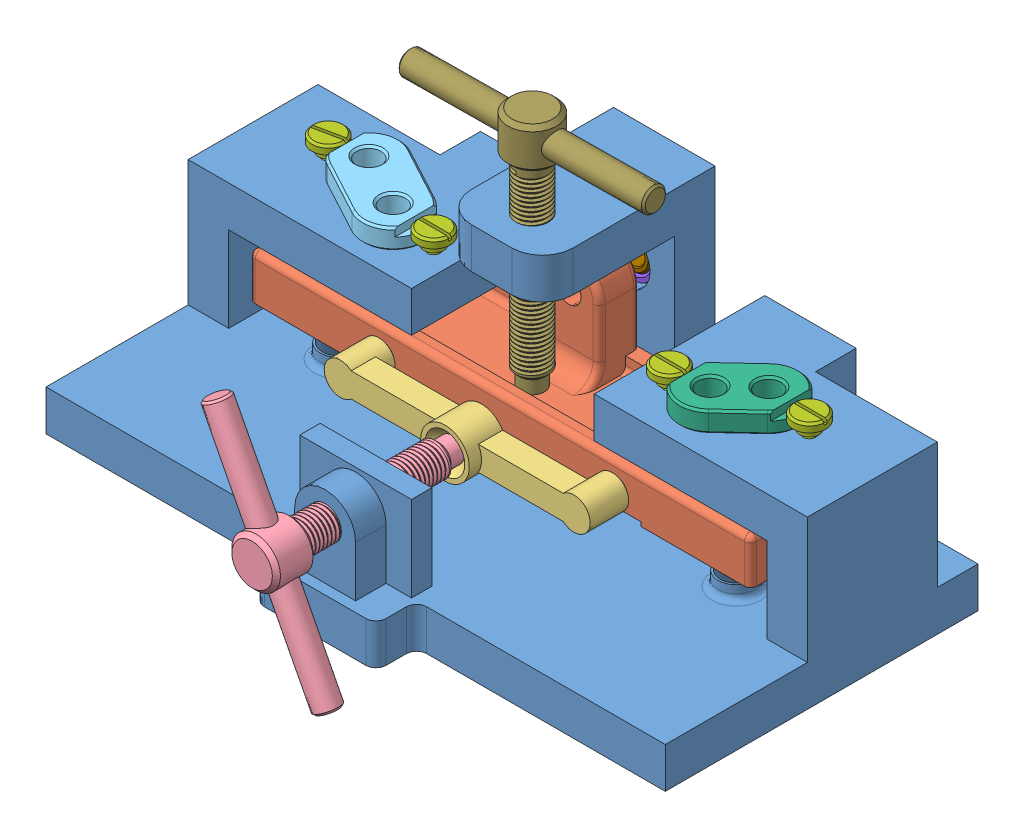
SolidWorks assembly 钻床夹具装配体1, configuration 默认. Lengths in mm.
Overall size (305 182.8 215).
22 component instances, 14 part files, 47 mates.
Components (placement in the parent):
- 钻床夹具（改）-1: 钻床夹具（改） [默认] at (208.9137 157.1071 193.3387) x (1 0 0) z (0 1 0) size (305 174 125.59)
- 前横架-1: 前横架 [默认] at (331.4137 192.1071 164.3387) x (-1 0 0) z (0 1 0) size (247 54 64)
- 压紧杆-1: 压紧杆 [默认] at (151.4137 203.1071 228.3387) size (131 24 28)
- 固定手柄压紧螺钉-1: 固定手柄压紧螺钉 [默认] at (208.9137 203.1071 341.3387) x (-0.887983 -0.459876 0) z (-0.459876 0.887983 0) size (24 100 120)
- 特殊钻套1-1: 特殊钻套1 [默认] at (135.4137 223.1071 198.3387) x (1 0 0) z (0 1 0) size (56 44 26)
- 特殊钻套2-1: 特殊钻套2 [默认] at (291.4137 223.1071 198.3387) x (1 0 0) z (0 1 0) size (45 44 26)
- 钻套螺钉M6×4-1: 钻套螺钉M6×4 [默认] at (89.4137 231.1071 184.3387) x (0.979036 0 -0.203686) z (0.203686 0 0.979036) size (16 18 16)
- 钻套螺钉M6×4-2: 钻套螺钉M6×4 [默认] at (155.4137 231.1071 198.3387) size (16 18 16)
- 钻套螺钉M6×4-3: 钻套螺钉M6×4 [默认] at (271.4137 231.1071 198.3387) size (16 18 16)
- 钻套螺钉M6×4-4: 钻套螺钉M6×4 [默认] at (326.4137 231.1071 184.3387) size (16 18 16)
- 衬套-1: 衬套 [默认] at (206.9137 241.1071 152.3387) x (1 0 0) z (0 1 0) size (30 16 30)
- 可换钻套-1: 可换钻套 [默认] at (206.9137 241.1071 152.3387) x (-0.095615 -0.995418 0) z (0.995418 -0.095615 0) size (30 26 30)
- 钻套螺钉M6×4-5: 钻套螺钉M6×4 [默认] at (206.9137 221.1071 144.3387) x (0.928637 -0.37099 0) z (0.37099 0.928637 0) size (16 18 16)
- A型支承钉-1: A型支承钉 [默认] at (131.4137 192.1071 176.3387) size (16 20 16)
- A型支承钉-2: A型支承钉 [默认] at (116.4137 192.1071 206.3387) size (16 20 16)
- A型支承钉-3: A型支承钉 [默认] at (311.4137 192.1071 205.3387) size (16 20 16)
- 辅助支撑螺柱-1: 辅助支撑螺柱 [默认] at (206.9137 173.7633 201.3387) x (0.999421 0 0.034011) z (-0.034011 0 0.999421) size (10 40 10)
- Z向夹紧手柄-2: Z向夹紧手柄 [默认] at (206.9137 327.1071 201.3387) x (-0.009902 0 -0.999951) z (0.999951 0 -0.009902) size (24 120 120)
- hex nuts, style 1-grades ab gb-1: hex nuts, style 1-grades ab gb [GB_FASTENER_NUT_SNAB1 M10-S] at (206.9137 177.1071 201.3387) x (1 0 0) z (0 -1 0) size (18.48 16 8.4)
- B型支承钉-1: B型支承钉 [默认] at (84.4137 203.1071 193.3387) x (0 -1 0) z (0 0 1) size (16 20 16)
- B型支承钉-2: B型支承钉 [默认] at (141.4137 203.1071 164.3387) x (1 0 0) z (0 -1 0) size (16 20 16)
- B型支承钉-3: B型支承钉 [默认] at (276.4137 203.1071 164.3387) x (1 0 0) z (0 -1 0) size (16 20 16)
Mates (geometry in assembly coordinates):
- 同心1: concentric: cylinder of assembly; cylinder of assembly; cylinder of 钻床夹具（改）-1 through (131.4137 157.1071 176.3387) axis (0 1 0) radius 5; cylinder of A型支承钉-1 through (131.4137 172.1071 176.3387) axis (0 -1 0) radius 5
- 重合1: coincident: plane of assembly; plane of assembly; plane of 钻床夹具（改）-1 through (131.4137 184.1071 176.3387) normal (0 1 0); plane of A型支承钉-1 through (139.4137 184.1071 176.3387) normal (0 -1 0)
- 同心2: concentric: cylinder of assembly; cylinder of assembly; cylinder of 钻床夹具（改）-1 through (116.4137 157.1071 206.3387) axis (0 1 0) radius 5; cylinder of A型支承钉-2 through (116.4137 172.1071 206.3387) axis (0 -1 0) radius 5
- 重合2: coincident: plane of assembly; plane of assembly; plane of 钻床夹具（改）-1 through (116.4137 184.1071 206.3387) normal (0 1 0); plane of A型支承钉-2 through (124.4137 184.1071 206.3387) normal (0 -1 0)
- 同心3: concentric: cylinder of assembly; cylinder of assembly; cylinder of 钻床夹具（改）-1 through (311.4137 157.1071 205.3387) axis (0 1 0) radius 5; cylinder of A型支承钉-3 through (311.4137 172.1071 205.3387) axis (0 -1 0) radius 5
- 重合3: coincident: plane of assembly; plane of assembly; plane of 钻床夹具（改）-1 through (311.4137 184.1071 205.3387) normal (0 1 0); plane of A型支承钉-3 through (319.4137 184.1071 205.3387) normal (0 -1 0)
- 同心4: concentric: cylinder of assembly; cylinder of assembly; cylinder of 钻床夹具（改）-1 through (291.4137 157.1061 198.3387) axis (0 1 0) radius 9; cylinder of 特殊钻套2-1 through (291.4137 239.1071 198.3387) axis (0 -1 0) radius 9
- 同心5: concentric: cylinder of assembly; cylinder of assembly; cylinder of 钻床夹具（改）-1 through (306.4137 157.1061 184.3387) axis (0 1 0) radius 9; cylinder of 特殊钻套2-1 through (306.4137 239.1071 184.3387) axis (0 -1 0) radius 9
- 重合5: coincident: plane of assembly; plane of assembly; plane of 钻床夹具（改）-1 through (208.9137 239.1071 193.3387) normal (0 1 0); plane of 特殊钻套2-1 through (291.4137 239.1071 198.3387) normal (0 -1 0)
- 同心6: concentric: cylinder of assembly; cylinder of assembly; cylinder of 钻床夹具（改）-1 through (135.4137 157.1061 198.3387) axis (0 1 0) radius 9; cylinder of 特殊钻套1-1 through (135.4137 239.1071 198.3387) axis (0 -1 0) radius 9
- 同心7: concentric: cylinder of assembly; cylinder of assembly; cylinder of 钻床夹具（改）-1 through (109.4137 157.1061 184.3387) axis (0 1 0) radius 9; cylinder of 特殊钻套1-1 through (109.4137 239.1071 184.3387) axis (0 -1 0) radius 9
- 重合6: coincident: plane of assembly; plane of assembly; plane of 钻床夹具（改）-1 through (208.9137 239.1071 193.3387) normal (0 1 0); plane of 特殊钻套1-1 through (135.4137 239.1071 198.3387) normal (0 -1 0)
- 同心8: concentric: cylinder of assembly; cylinder of assembly; cylinder of 钻床夹具（改）-1 through (271.4137 229.1071 198.3387) axis (0 1 0) radius 3; cylinder of 钻套螺钉M6×4-3 through (271.4137 249.1071 198.3387) axis (0 1 0) radius 3
- 重合7: coincident: plane of assembly; plane of assembly; plane of 特殊钻套2-1 through (291.4137 245.1071 198.3387) normal (0 1 0); plane of 钻套螺钉M6×4-3 through (276.1637 245.1071 198.3387) normal (0 -1 0)
- 同心9: concentric: cylinder of assembly; cylinder of assembly; cylinder of 钻床夹具（改）-1 through (326.4137 229.1071 184.3387) axis (0 1 0) radius 3; cylinder of 钻套螺钉M6×4-4 through (326.4137 249.1071 184.3387) axis (0 1 0) radius 3
- 重合8: coincident: plane of assembly; plane of assembly; plane of 特殊钻套2-1 through (306.4137 245.1071 184.3387) normal (0 1 0); plane of 钻套螺钉M6×4-4 through (331.1637 245.1071 184.3387) normal (0 -1 0)
- 同心10: concentric: cylinder of assembly; cylinder of assembly; cylinder of 钻床夹具（改）-1 through (155.4137 229.1071 198.3387) axis (0 1 0) radius 3; cylinder of 钻套螺钉M6×4-2 through (155.4137 249.1071 198.3387) axis (0 1 0) radius 3
- 重合9: coincident: plane of assembly; plane of assembly; plane of 特殊钻套1-1 through (135.4137 245.1071 198.3387) normal (0 1 0); plane of 钻套螺钉M6×4-2 through (160.1637 245.1071 198.3387) normal (0 -1 0)
- 同心11: concentric: cylinder of assembly; cylinder of assembly; cylinder of 钻床夹具（改）-1 through (89.4137 229.1071 184.3387) axis (0 1 0) radius 3; cylinder of 钻套螺钉M6×4-1 through (89.4137 249.1071 184.3387) axis (0 1 0) radius 3
- 重合10: coincident: plane of assembly; plane of assembly; plane of 特殊钻套1-1 through (109.4137 245.1071 184.3387) normal (0 1 0); plane of 钻套螺钉M6×4-1 through (94.0641 245.1071 183.3712) normal (0 -1 0)
- 同心12: concentric: cylinder of assembly; cylinder of assembly; cylinder of 钻床夹具（改）-1 through (361.4147 203.1071 193.3387) axis (-1 0 0) radius 5; cylinder of B型支承钉-1 through (64.4137 203.1071 193.3387) axis (-1 0 0) radius 5
- 重合11: coincident: plane of assembly; plane of assembly; plane of 钻床夹具（改）-1 through (76.4137 219.1071 193.3387) normal (1 0 0); plane of B型支承钉-1 through (76.4137 195.1071 193.3387) normal (-1 0 0)
- 同心13: concentric: cylinder of assembly; cylinder of assembly; cylinder of 钻床夹具（改）-1 through (141.4137 203.1071 310.3397) axis (0 0 -1) radius 5; cylinder of B型支承钉-2 through (141.4137 203.1071 144.3387) axis (0 0 -1) radius 5
- 重合12: coincident: plane of assembly; plane of assembly; plane of 钻床夹具（改）-1 through (166.4137 219.1071 156.3387) normal (0 0 1); plane of B型支承钉-2 through (149.4137 203.1071 156.3387) normal (0 0 -1)
- 同心14: concentric: cylinder of assembly; cylinder of assembly; cylinder of 钻床夹具（改）-1 through (276.4137 203.1071 310.3397) axis (0 0 -1) radius 5; cylinder of B型支承钉-3 through (276.4137 203.1071 144.3387) axis (0 0 -1) radius 5
- 重合13: coincident: plane of assembly; plane of assembly; plane of 钻床夹具（改）-1 through (208.9137 219.1071 156.3387) normal (0 0 1); plane of B型支承钉-3 through (284.4137 203.1071 156.3387) normal (0 0 -1)
- 同心15: concentric: cylinder of assembly; cylinder of assembly; cylinder of 钻床夹具（改）-1 through (206.9137 241.1071 156.3387) axis (0 0 -1) radius 13; cylinder of 衬套-1 through (206.9137 241.1071 136.3387) axis (0 0 -1) radius 13
- 重合14: coincident: plane of assembly; plane of assembly; plane of 钻床夹具（改）-1 through (206.9137 241.1071 139.3387) normal (0 0 -1); plane of 衬套-1 through (218.9137 241.1071 139.3387) normal (0 0 1)
- 同心16: concentric: cylinder of assembly; cylinder of assembly; cylinder of 衬套-1 through (206.9137 241.1071 152.3387) axis (0 0 -1) radius 9; cylinder of 可换钻套-1 through (206.9137 241.1071 126.3387) axis (0 0 -1) radius 9
- 重合15: coincident: plane of assembly; plane of assembly; plane of 衬套-1 through (221.9137 241.1071 136.3387) normal (0 0 -1); plane of 可换钻套-1 through (206.9137 241.1071 136.3387) normal (0 0 1)
- 同心17: concentric: cylinder of assembly; cylinder of assembly; cylinder of 钻床夹具（改）-1 through (206.9137 221.1071 151.3387) axis (0 0 -1) radius 3; cylinder of 钻套螺钉M6×4-5 through (206.9137 221.1071 126.3387) axis (0 0 -1) radius 3
- 重合16: coincident: plane of assembly; plane of assembly; plane of 可换钻套-1 through (206.9137 241.1071 130.3387) normal (0 0 -1); plane of 钻套螺钉M6×4-5 through (211.3247 219.3449 130.3387) normal (0 0 1)
- 重合17: coincident: plane of assembly; plane of assembly; plane of 前横架-1 through (331.4137 192.1071 164.3387) normal (0 -1 0); plane of A型支承钉-2 through (116.4137 192.1071 206.3387) normal (0 1 0)
- 相切1: tangent: plane of assembly; sphere of assembly; plane of 前横架-1 through (84.4137 214.1071 164.3387) normal (-1 0 0); sphere of B型支承钉-1
- 相切2: tangent: plane of assembly; sphere of assembly; plane of 前横架-1 through (331.4137 214.1071 164.3387) normal (0 0 -1); sphere of B型支承钉-3
- 同心18: concentric: circle of assembly; circle of assembly; circle of 钻床夹具（改）-1; circle of 辅助支撑螺柱-1
- 重合19: coincident: plane of assembly; plane of assembly; plane of 钻床夹具（改）-1 through (173.9137 177.1071 295.3387) normal (0 1 0); plane of hex nuts, style 1-grades ab gb-1 through (206.9137 177.1071 185.3387) normal (0 -1 0)
- 同心19: concentric: circle of assembly; circle of assembly; circle of 辅助支撑螺柱-1; circle of hex nuts, style 1-grades ab gb-1
- 相切3: tangent: plane of assembly; sphere of assembly; plane of 前横架-1 through (331.4137 201.1071 164.3387) normal (0 -1 0); sphere of 辅助支撑螺柱-1
- 相切4: tangent: plane of assembly; sphere of assembly; plane of 前横架-1 through (331.4137 214.1071 218.3387) normal (0 0 1); sphere of 压紧杆-1
- 相切5: tangent: plane of assembly; sphere of assembly; plane of 前横架-1 through (331.4137 214.1071 218.3387) normal (0 0 1); sphere of 压紧杆-1
- 平行1: parallel: plane of assembly; plane of assembly; plane of 钻床夹具（改）-1 through (173.9137 177.1071 295.3387) normal (0 1 0); plane of 压紧杆-1 through (151.4137 209.1071 240.3387) normal (0 1 0)
- 同心20: concentric: sphere of assembly; sphere of assembly; sphere of 压紧杆-1; sphere of 固定手柄压紧螺钉-1
- 同心21: concentric: circle of assembly; cylinder of assembly; circle of 钻床夹具（改）-1; cylinder of 固定手柄压紧螺钉-1 through (208.9137 203.1071 341.3387) axis (0 0 1) radius 12
- 同心22: concentric: circle of assembly; cylinder of assembly; circle of 钻床夹具（改）-1; cylinder of Z向夹紧手柄-2 through (206.9137 327.1071 201.3387) axis (0 1 0) radius 6
- 相切6: tangent: plane of assembly; sphere of assembly; plane of 前横架-1 through (331.4137 207.1071 164.3387) normal (0 1 0); sphere of Z向夹紧手柄-2
- 相切7: tangent: plane of assembly; sphere of assembly; plane of 前横架-1 through (331.4137 214.1071 164.3387) normal (0 0 -1); sphere of B型支承钉-2
